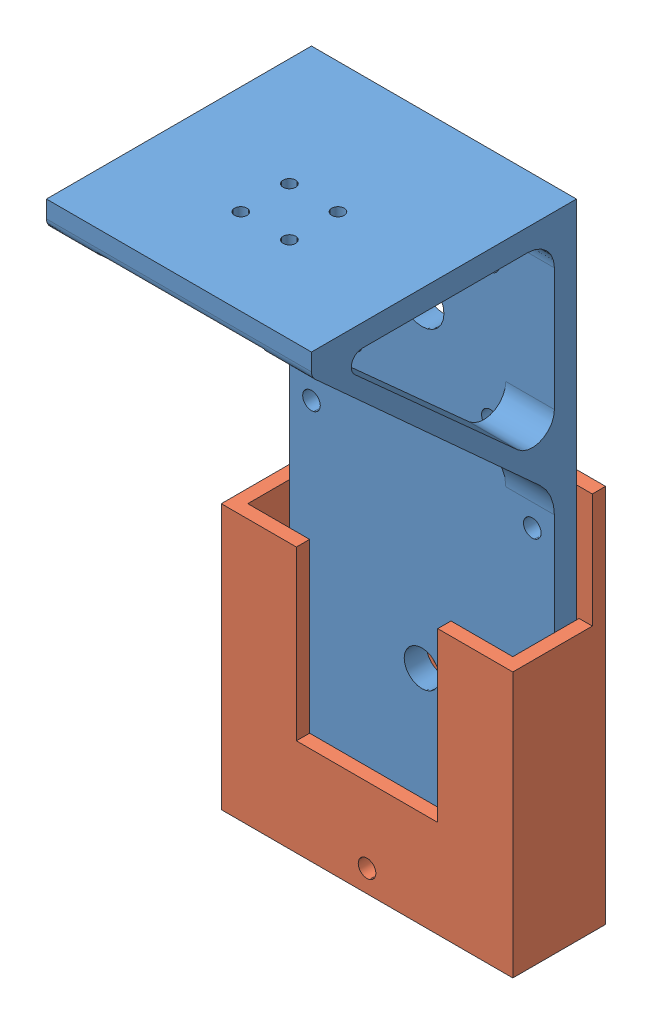
SolidWorks assembly Assem1, configuration Default. Lengths in mm.
Overall size (66 142.51 63.57).
2 component instances, 2 part files, 0 mates.
Components (placement in the parent):
- lbracket_v1-2: lbracket_v1 [Default] at (68.9671 82.5712 123.9066) size (60 142.4 60)
- lbrac_attach_v1-2: lbrac_attach_v1 [Default] at (71.9838 92.4594 80.806) size (66 85.9 21)
